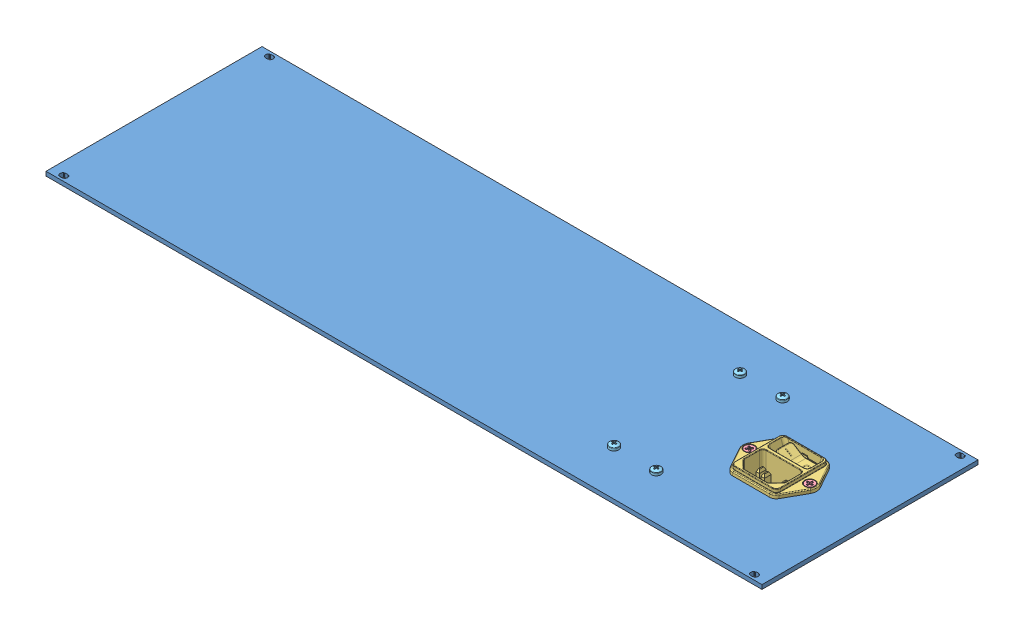
SolidWorks assembly MLA-0387-M2, configuration Default. Lengths in mm.
Overall size (426.52 36.95 128.7).
23 component instances, 9 part files, 36 mates.
Components (placement in the parent):
- MLA-0387-M3-1: MLA-0387-M3 [Default] at (14.077 -174.6299 585.4715) size (426.52 2.5 128.7)
- ECL15US12-S-1: ECL15US12-S [Default] at (340.987 202.9701 302.5215) x (0 0 -1) z (1 0 0) size (84 26.49 34.5)
- DC11_0001_001-1: DC11_0001_001 [Default] at (389.437 205.4701 308.5715) x (1 0 0) z (0 1 0) size (44 34 36.95)
- SCREW_ISO 7046-1: SCREW_ISO 7046 [VIJAK M 3x 10] at (371.437 207.6701 302.5215) x (0 -1 0) z (-0.609119 0 0.793079) size (10 5.6 5.6)
- SCREW_ISO 7046-2: SCREW_ISO 7046 [VIJAK M 3x 10] at (407.437 207.6701 302.5215) x (0 -1 0) z (0 0 1) size (10 5.6 5.6)
- M3 X 10mm Screw-1: M3 X 10mm Screw [Default] at (328.287 207.8701 340.0215) x (0 -1 0) z (0 0 1) size (12.61 5.6 5.6)
- M3 X 10mm Screw-2: M3 X 10mm Screw [Default] at (353.687 207.8701 340.2611) x (0 -1 0) z (0 0 1) size (12.61 5.6 5.6)
- M3 X 10mm Screw-3: M3 X 10mm Screw [Default] at (353.687 207.8701 265.0215) x (0 -1 0) z (0 0 1) size (12.61 5.6 5.6)
- M3 X 10mm Screw-4: M3 X 10mm Screw [Default] at (328.287 207.8701 265.0215) x (0 -1 0) z (0 0 1) size (12.61 5.6 5.6)
- M3 screw size FLAT WASHER-1: M3 screw size FLAT WASHER [Default] at (407.437 202.9701 302.5215) x (0.944963 0 -0.327176) z (0 -1 0) size (7 7 0.6)
- M3 screw size FLAT WASHER-2: M3 screw size FLAT WASHER [Default] at (371.437 202.3701 302.5215) x (1 0 0) z (0 1 0) size (7 7 0.6)
- M3 x 0.5mm Thread HEX NUT-1: M3 x 0.5mm Thread HEX NUT [Default] at (407.4348 201.1701 302.5562) x (1 0 0) z (0 1 0) size (5.5 6.35 2.6)
- M3 x 0.5mm Thread HEX NUT-2: M3 x 0.5mm Thread HEX NUT [Default] at (371.4463 201.1701 302.55) x (1 0 0) z (0 1 0) size (5.5 6.35 2.6)
- M3 screw size FLAT WASHER-3: M3 screw size FLAT WASHER [Default] at (353.687 199.8701 340.2611) x (1 0 0) z (0 1 0) size (7 7 0.6)
- M3 screw size FLAT WASHER-4: M3 screw size FLAT WASHER [Default] at (328.287 199.8701 340.0215) x (1 0 0) z (0 1 0) size (7 7 0.6)
- M3 screw size FLAT WASHER-5: M3 screw size FLAT WASHER [Default] at (328.287 200.4701 265.0215) x (1 0 0) z (0 -1 0) size (7 7 0.6)
- M3 screw size FLAT WASHER-6: M3 screw size FLAT WASHER [Default] at (353.687 200.4701 265.0215) x (1 0 0) z (0 -1 0) size (7 7 0.6)
- M3 x 0.5mm Thread HEX NUT-3: M3 x 0.5mm Thread HEX NUT [Default] at (328.3059 198.6701 265.0157) x (1 0 0) z (0 -1 0) size (5.5 6.35 2.6)
- M3 x 0.5mm Thread HEX NUT-4: M3 x 0.5mm Thread HEX NUT [Default] at (353.679 198.6701 264.9262) x (1 0 0) z (0 -1 0) size (5.5 6.35 2.6)
- M3 x 0.5mm Thread HEX NUT-5: M3 x 0.5mm Thread HEX NUT [Default] at (353.654 198.6701 340.285) x (1 0 0) z (0 1 0) size (5.5 6.35 2.6)
- M3 x 0.5mm Thread HEX NUT-6: M3 x 0.5mm Thread HEX NUT [Default] at (328.2745 198.6701 340.0301) x (1 0 0) z (0 1 0) size (5.5 6.35 2.6)
- MLA-0387-C1-1: MLA-0387-C1 [Default] at (14.9012 211.109 380.7327)
- MLA-0387-C2-1: MLA-0387-C2 [Default] at (65.7499 212.3525 388.3966)
Mates (geometry in assembly coordinates):
- Coincident1: coincident anti-aligned: plane of MLA-0387-M3-1 through (22.1573 202.9701 282.3956) normal (0 -1 0); plane of ECL15US12-S-1 through (358.237 202.9701 335.5215) normal (0 1 0)
- Distance1: distance = 22.35 mm aligned: line of ECL15US12-S-1 through (324.7368 202.9701 344.5215) axis (1 0 0); plane of MLA-0387-M3-1 through (443.237 202.9701 366.8715) normal (0 0 1)
- Coincident8: coincident anti-aligned: plane of MLA-0387-M3-1 through (22.1573 205.4701 282.3956) normal (0 1 0); plane of DC11_0001_001-1 through (378.437 205.4701 289.5215) normal (0 -1 0)
- Concentric2: concentric anti-aligned: cylinder of MLA-0387-M3-1 through (371.437 212.9701 302.5215) axis (0 -1 0) radius 1.8; cylinder of DC11_0001_001-1 through (371.437 207.6701 302.5215) axis (0 1 0) radius 1.6
- Concentric3: concentric anti-aligned: cylinder of MLA-0387-M3-1 through (407.437 212.9701 302.5215) axis (0 -1 0) radius 1.8; cylinder of DC11_0001_001-1 through (407.437 207.6701 302.5215) axis (0 1 0) radius 1.6
- Distance4: distance = 85 mm: line of MLA-0387-M3-1 through (443.237 202.9701 366.8715) axis (0 0 -1); line of ECL15US12-S-1 through (358.237 202.9701 343.5217) axis (0 0 -1)
- Concentric4: concentric aligned: cone of DC11_0001_001-1 through (371.437 207.4701 302.5215) axis (0 -1 0); cone of SCREW_ISO 7046-1 through (371.437 206.1701 302.5215) axis (0 -1 0)
- Coincident9: coincident aligned: plane of DC11_0001_001-1 through (378.437 207.6701 289.5215) normal (0 1 0); plane of SCREW_ISO 7046-1 through (371.437 207.6701 302.5215) normal (0 1 0)
- Concentric5: concentric aligned: cone of DC11_0001_001-1 through (407.437 207.4701 302.5215) axis (0 -1 0); cone of SCREW_ISO 7046-2 through (407.437 206.1701 302.5215) axis (0 -1 0)
- Coincident10: coincident aligned: plane of DC11_0001_001-1 through (378.437 207.6701 289.5215) normal (0 1 0); plane of SCREW_ISO 7046-2 through (407.437 207.6701 302.5215) normal (0 1 0)
- Coincident11: coincident anti-aligned: plane of MLA-0387-M3-1 through (22.1573 205.4701 282.3956) normal (0 1 0); plane of M3 X 10mm Screw-1 through (328.287 205.4701 338.5215) normal (0 -1 0)
- Concentric6: concentric aligned: cylinder of MLA-0387-M3-1 through (328.287 212.9701 340.0215) axis (0 -1 0) radius 1.8; cylinder of M3 X 10mm Screw-1 through (328.287 195.4701 340.0215) axis (0 -1 0) radius 2.8
- Coincident12: coincident anti-aligned: plane of MLA-0387-M3-1 through (22.1573 205.4701 282.3956) normal (0 1 0); plane of M3 X 10mm Screw-2 through (353.687 205.4701 338.7611) normal (0 -1 0)
- Concentric7: concentric aligned: cylinder of MLA-0387-M3-1 through (353.687 212.9701 340.2611) axis (0 -1 0) radius 1.8; cylinder of M3 X 10mm Screw-2 through (353.687 195.4701 340.2611) axis (0 -1 0) radius 2.8
- Coincident13: coincident anti-aligned: plane of MLA-0387-M3-1 through (22.1573 205.4701 282.3956) normal (0 1 0); plane of M3 X 10mm Screw-3 through (353.687 205.4701 263.5215) normal (0 -1 0)
- Concentric8: concentric aligned: cylinder of MLA-0387-M3-1 through (353.687 212.9701 265.0215) axis (0 -1 0) radius 1.8; cylinder of M3 X 10mm Screw-3 through (353.687 195.4701 265.0215) axis (0 -1 0) radius 2.8
- Coincident14: coincident anti-aligned: plane of MLA-0387-M3-1 through (22.1573 205.4701 282.3956) normal (0 1 0); plane of M3 X 10mm Screw-4 through (328.287 205.4701 263.5215) normal (0 -1 0)
- Concentric9: concentric aligned: cylinder of MLA-0387-M3-1 through (328.287 212.9701 265.0215) axis (0 -1 0) radius 1.8; cylinder of M3 X 10mm Screw-4 through (328.287 195.4701 265.0215) axis (0 -1 0) radius 2.8
- Coincident15: coincident anti-aligned: plane of MLA-0387-M3-1 through (22.1573 202.9701 282.3956) normal (0 -1 0); plane of M3 screw size FLAT WASHER-1 through (407.437 202.9701 302.5215) normal (0 1 0)
- Concentric10: concentric anti-aligned: cylinder of M3 screw size FLAT WASHER-1 through (407.437 202.3701 302.5215) axis (0 1 0) radius 1.6; cylinder of SCREW_ISO 7046-2 through (407.437 197.6701 302.5215) axis (0 -1 0) radius 2.8
- Coincident16: coincident anti-aligned: plane of MLA-0387-M3-1 through (22.1573 202.9701 282.3956) normal (0 -1 0); plane of M3 screw size FLAT WASHER-2 through (371.437 202.9701 302.5215) normal (0 1 0)
- Concentric11: concentric aligned: cylinder of MLA-0387-M3-1 through (371.437 212.9701 302.5215) axis (0 -1 0) radius 1.8; cylinder of M3 screw size FLAT WASHER-2 through (371.437 202.9701 302.5215) axis (0 -1 0) radius 1.6
- Coincident17: coincident anti-aligned: plane of M3 screw size FLAT WASHER-1 through (407.437 202.3701 302.5215) normal (0 -1 0); plane of M3 x 0.5mm Thread HEX NUT-1 through (404.6848 202.3701 300.9685) normal (0 1 0)
- Coincident18: coincident anti-aligned: plane of M3 screw size FLAT WASHER-2 through (371.437 202.3701 302.5215) normal (0 -1 0); plane of M3 x 0.5mm Thread HEX NUT-2 through (368.6963 202.3701 300.9623) normal (0 1 0)
- Coincident19: coincident anti-aligned: plane of ECL15US12-S-1 through (358.237 200.4701 335.0215) normal (0 -1 0); plane of M3 screw size FLAT WASHER-3 through (353.687 200.4701 340.2611) normal (0 1 0)
- Concentric13: concentric aligned: cylinder of M3 X 10mm Screw-2 through (353.687 195.4701 340.2611) axis (0 -1 0) radius 2.8; cylinder of M3 screw size FLAT WASHER-3 through (353.687 200.4701 340.2611) axis (0 -1 0) radius 3.5
- Coincident20: coincident anti-aligned: plane of ECL15US12-S-1 through (358.237 200.4701 335.0215) normal (0 -1 0); plane of M3 screw size FLAT WASHER-4 through (328.287 200.4701 340.0215) normal (0 1 0)
- Concentric14: concentric aligned: cylinder of M3 X 10mm Screw-1 through (328.287 195.4701 340.0215) axis (0 -1 0) radius 2.8; cylinder of M3 screw size FLAT WASHER-4 through (328.287 200.4701 340.0215) axis (0 -1 0) radius 3.5
- Coincident21: coincident anti-aligned: plane of ECL15US12-S-1 through (358.237 200.4701 270.0215) normal (0 -1 0); plane of M3 screw size FLAT WASHER-5 through (328.287 200.4701 265.0215) normal (0 1 0)
- Concentric15: concentric aligned: cylinder of M3 X 10mm Screw-4 through (328.287 195.4701 265.0215) axis (0 -1 0) radius 2.8; circle of M3 screw size FLAT WASHER-5
- Coincident22: coincident anti-aligned: plane of ECL15US12-S-1 through (358.237 200.4701 270.0215) normal (0 -1 0); plane of M3 screw size FLAT WASHER-6 through (353.687 200.4701 265.0215) normal (0 1 0)
- Concentric16: concentric anti-aligned: circle of M3 X 10mm Screw-3; cylinder of M3 screw size FLAT WASHER-6 through (353.687 199.8701 265.0215) axis (0 1 0) radius 3.5
- Coincident24: coincident anti-aligned: plane of M3 screw size FLAT WASHER-5 through (328.287 199.8701 265.0215) normal (0 -1 0); plane of M3 x 0.5mm Thread HEX NUT-3 through (325.5559 199.8701 266.6034) normal (0 1 0)
- Coincident25: coincident anti-aligned: plane of M3 screw size FLAT WASHER-6 through (353.687 199.8701 265.0215) normal (0 -1 0); plane of M3 x 0.5mm Thread HEX NUT-4 through (350.929 199.8701 266.5139) normal (0 1 0)
- Coincident26: coincident anti-aligned: plane of M3 screw size FLAT WASHER-3 through (353.687 199.8701 340.2611) normal (0 -1 0); plane of M3 x 0.5mm Thread HEX NUT-5 through (350.904 199.8701 338.6973) normal (0 1 0)
- Coincident27: coincident anti-aligned: plane of M3 screw size FLAT WASHER-4 through (328.287 199.8701 340.0215) normal (0 -1 0); plane of M3 x 0.5mm Thread HEX NUT-6 through (325.5245 199.8701 338.4424) normal (0 1 0)
